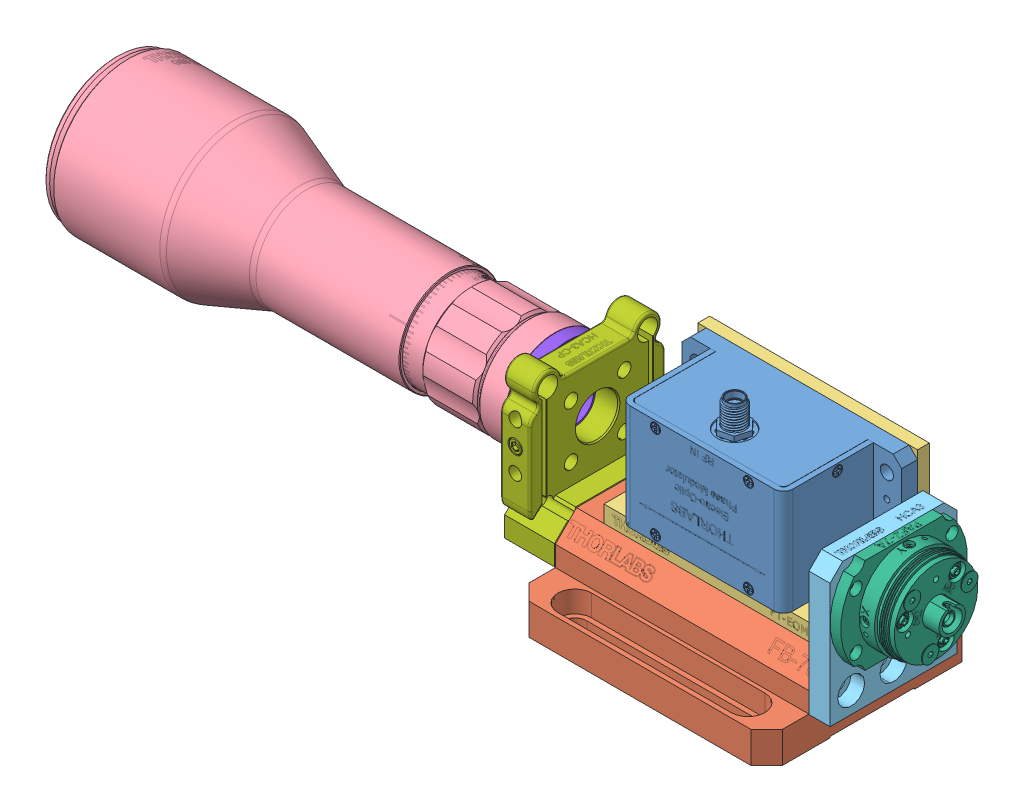
SolidWorks assembly Modulator Total, configuration Default. Lengths in mm.
Overall size (251.21 68.2 63.5).
8 component instances, 8 part files, 19 mates.
Components (placement in the parent):
- EO-PM-NR-C4 - PhaseModulator-1: EO-PM-NR-C4 - PhaseModulator [Default] at (-72.0553 90.4481 108.1594) x (0 1 0) z (1 0 0) size (40.01 31.79 66.04)
- FB-76 - FiberBench-1: FB-76 - FiberBench [Default] at (-75.2303 51.0781 123.6534) size (76.2 21.84 63.5)
- FT-EOMA - AdapterBracket-1: FT-EOMA - AdapterBracket [Default] at (-72.0553 87.2731 120.4784) x (0 0 -1) z (1 0 0) size (31.75 42.23 66.04)
- GBE10-A - BeamExpander10-1: GBE10-A - BeamExpander10 [Default] at (-131.3323 82.5741 123.6788) x (0 0.524395 0.851475) z (-1 0 0) size (45 45 135)
- HCA3 - WallPlate-1: HCA3 - WallPlate [Default] at (-30.7803 55.6501 142.7034) x (0 0 1) z (-1 0 0) size (38.1 41.15 6.35)
- PAF2-7A - FiberCollimator123um-1: PAF2-7A - FiberCollimator123um [Default] at (-19.8583 82.5233 123.6534) x (0 -1 0) z (1 0 0) size (28.58 38.1 18.91)
- HCA3-CP - CageWallPlate-1: HCA3-CP - CageWallPlate [Default] at (-128.5703 82.5233 123.6509) x (0 0 1) z (-1 0 0) size (40.64 45.86 15.3)
- SM1A1 - ExSM05IntSM1-1: SM1A1 - ExSM05IntSM1 [Default] at (-128.5703 82.5233 123.6509) x (0 0.399109 -0.916903) z (1 0 0) size (30.48 30.48 6.35)
Mates (geometry in assembly coordinates):
- Concentric1: concentric: cylinder of FB-76 - FiberBench-1 through (-64.6893 61.1111 130.0034) axis (0 1 0) radius 1.5938; cylinder of FT-EOMA - AdapterBracket-1 through (-64.6893 64.0956 130.0034) axis (0 -1 0) radius 1.5875
- Concentric2: concentric: cylinder of FB-76 - FiberBench-1 through (-64.6893 61.1111 117.3034) axis (0 1 0) radius 1.6002; cone of FT-EOMA - AdapterBracket-1 through (-64.6893 64.6036 117.3034) axis (0 -1 0)
- Coincident1: coincident: plane of FB-76 - FiberBench-1 through (-113.3303 68.2231 136.3534) normal (0 1 0); plane of FT-EOMA - AdapterBracket-1 through (-39.0353 68.2231 104.6034) normal (0 -1 0)
- Concentric3: concentric: cylinder of EO-PM-NR-C4 - PhaseModulator-1 through (-43.4803 100.6081 108.1584) axis (0 0 1) radius 1.9844; cylinder of FT-EOMA - AdapterBracket-1 through (-43.4803 100.6081 104.6034) axis (0 0 -1) radius 1.3526
- Concentric4: concentric: cylinder of EO-PM-NR-C4 - PhaseModulator-1 through (-100.6303 80.2881 108.1584) axis (0 0 1) radius 1.9844; cylinder of FT-EOMA - AdapterBracket-1 through (-100.6303 80.2881 104.6034) axis (0 0 -1) radius 1.3526
- Coincident2: coincident: plane of EO-PM-NR-C4 - PhaseModulator-1 through (-39.0353 74.5731 108.1594) normal (0 0 -1); plane of FT-EOMA - AdapterBracket-1 through (-105.0753 73.3031 108.1594) normal (0 0 1)
- Concentric5: concentric: cylinder of FB-76 - FiberBench-1 through (-37.1303 61.8731 136.3534) axis (1 0 0) radius 1.7272; cylinder of HCA3 - WallPlate-1 through (-37.1303 61.8731 136.3534) axis (1 0 0) radius 2.4003
- Concentric6: concentric: cylinder of FB-76 - FiberBench-1 through (-37.1303 61.8731 110.9534) axis (1 0 0) radius 1.7272; cylinder of HCA3 - WallPlate-1 through (-37.1303 61.8731 110.9534) axis (1 0 0) radius 2.4003
- Coincident3: coincident: plane of FB-76 - FiberBench-1 through (-37.1303 68.2231 104.6034) normal (1 0 0); plane of HCA3 - WallPlate-1 through (-37.1303 55.6501 142.7034) normal (-1 0 0)
- Concentric9: concentric: cylinder of HCA3 - WallPlate-1 through (-37.1303 82.5233 123.6534) axis (1 0 0) radius 12.573; cylinder of PAF2-7A - FiberCollimator123um-1 through (-85.2969 82.5233 123.6534) axis (1 0 0) radius 13.4874
- Parallel1: parallel: plane of HCA3 - WallPlate-1 through (-37.1303 96.7981 142.7034) normal (0 1 0); plane of PAF2-7A - FiberCollimator123um-1 through (-31.4153 96.8108 111.0531) normal (0 1 0)
- Coincident4: coincident: plane of HCA3 - WallPlate-1 through (-30.7803 55.6501 142.7034) normal (1 0 0); plane of PAF2-7A - FiberCollimator123um-1 through (-30.7803 82.5233 123.6534) normal (-1 0 0)
- Concentric10: concentric: cylinder of EO-PM-NR-C4 - PhaseModulator-1 through (-96.5663 82.5741 123.6788) axis (1 0 0) radius 1.1906; cylinder of GBE10-A - BeamExpander10-1 through (-132.8883 83.0045 121.039) axis (1 0 0) radius 15.25
- Concentric11: concentric: cylinder of FB-76 - FiberBench-1 through (-110.7903 61.8731 136.3534) axis (-1 0 0) radius 2.4003; cylinder of HCA3-CP - CageWallPlate-1 through (-113.3303 61.8731 136.3534) axis (-1 0 0) radius 2.4003
- Concentric12: concentric: cylinder of FB-76 - FiberBench-1 through (-113.3303 61.8731 110.9534) axis (-1 0 0) radius 1.7272; cylinder of HCA3-CP - CageWallPlate-1 through (-113.3303 61.8731 110.9534) axis (-1 0 0) radius 2.4003
- Coincident5: coincident: plane of FB-76 - FiberBench-1 through (-113.3303 68.2231 104.6034) normal (-1 0 0); plane of HCA3-CP - CageWallPlate-1 through (-113.3303 79.3368 123.6534) normal (1 0 0)
- Concentric13: concentric: cylinder of HCA3-CP - CageWallPlate-1 through (-113.3303 82.5233 123.6509) axis (-1 0 0) radius 6.4516; cylinder of SM1A1 - ExSM05IntSM1-1 through (-126.0303 82.5233 123.6509) axis (-1 0 0) radius 5.715
- Coincident6: coincident: plane of HCA3-CP - CageWallPlate-1 through (-128.5703 79.3368 123.6534) normal (-1 0 0); plane of SM1A1 - ExSM05IntSM1-1 through (-128.5703 82.5233 123.6509) normal (1 0 0)
- Coincident7: coincident: plane of GBE10-A - BeamExpander10-1 through (-129.3323 87.3663 119.3618) normal (1 0 0); plane of SM1A1 - ExSM05IntSM1-1 through (-129.3323 82.5233 123.6509) normal (-1 0 0)
